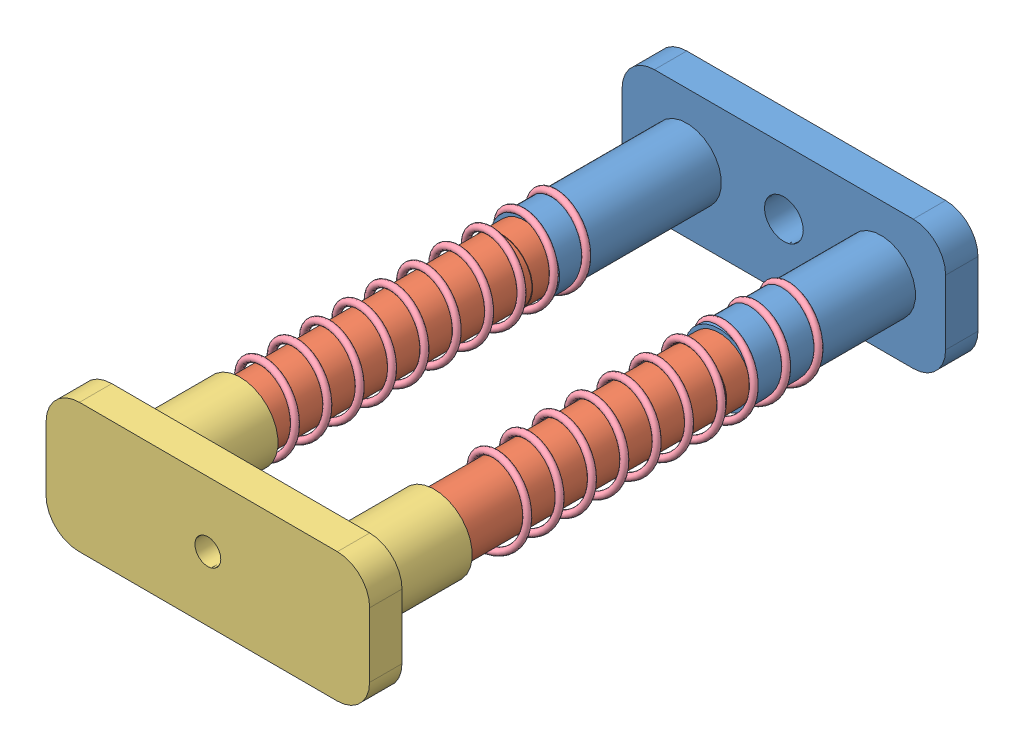
SolidWorks assembly assem3, configuration Default. Lengths in mm.
Overall size (50.03 20.07 94).
6 component instances, 4 part files, 7 mates.
Components (placement in the parent):
- mount 1-1: mount 1 [Default] at (83.1556 34.1999 -20.6338) size (50 20 30)
- mount 3-1: mount 3 [Default] at (74.1257 30.823 12.9837) x (0.99402 -0.109194 0) z (0 0 -1) size (9.6 9.6 49)
- mount2-1: mount2 [Default] at (66.1694 39.939 73.3662) x (0.999999 -0.001471 0) z (0 0 -1) size (50 20 20)
- spring-2: spring [Default] at (74.3292 31.0434 2.2218) x (0.374492 0.92723 0) z (0 0 1) size (13 13 51)
- mount 3-2: mount 3 [Default] at (104.1257 30.823 12.9837) x (-0.689119 -0.724648 0) z (0 0 -1) size (9.6 9.6 49)
- spring-3: spring [Default] at (104.4257 30.8209 -3.54) x (0.412087 0.911145 0) z (0 0 1) size (13 13 51)
Mates (geometry in assembly coordinates):
- Concentric4: concentric: cylinder of mount 1-1 through (74.1257 30.823 9.3662) axis (0 0 -1) radius 4.35; cylinder of mount 3-1 through (74.1257 30.823 7.9837) axis (0 0 1) radius 4.8
- Concentric8: concentric: cylinder of mount 1-1 through (104.1257 30.823 9.3662) axis (0 0 -1) radius 4.35; cylinder of mount 3-2 through (104.1257 30.823 56.9837) axis (0 0 -1) radius 4.7
- Tangent2: tangent: cylinder of mount 3-1 through (74.1257 30.823 56.9837) axis (0 0 -1) radius 4.7; face of spring-2
- Tangent7: tangent: cylinder of mount 3-2 through (104.1257 30.823 56.9837) axis (0 0 -1) radius 4.7; face of spring-3
- Concentric10: concentric: circle of mount 3-1; cylinder of mount2-1 through (74.1257 30.823 53.3662) axis (0 0 1) radius 4.85
- Concentric11: concentric: cylinder of mount2-1 through (104.1257 30.823 53.3662) axis (0 0 1) radius 4.85; circle of mount 3-2
- LimitDistance1: limit distance = 84 mm: plane of mount 1-1 through (69.1257 35.823 -15.6338) normal (0 0 1); plane of mount2-1 through (66.1694 39.939 68.3662) normal (0 0 -1)
